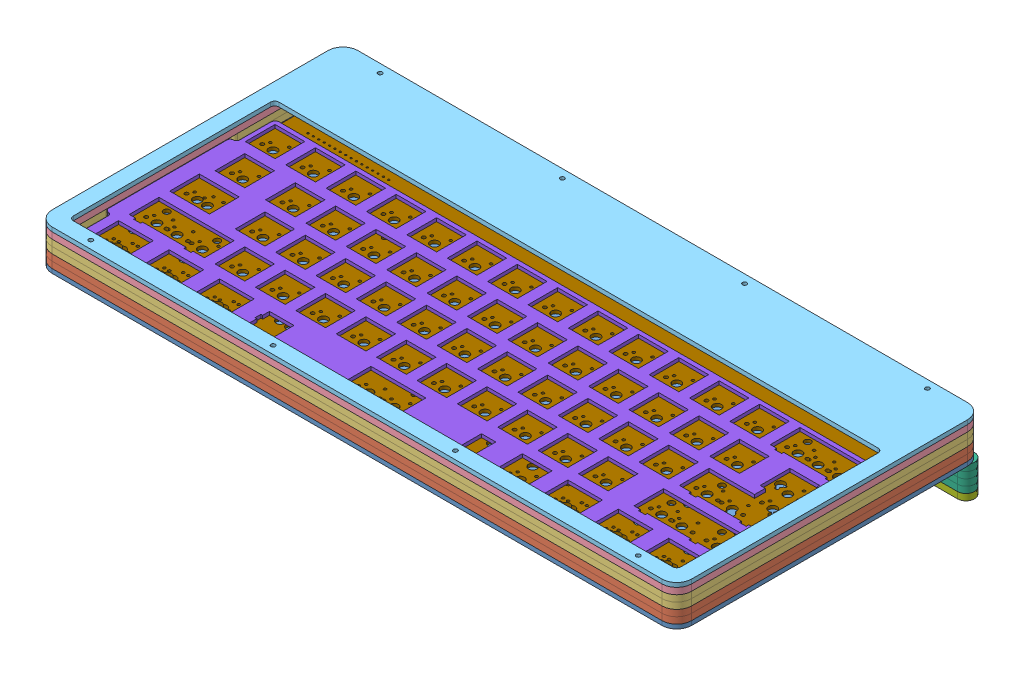
SolidWorks assembly case_stand, configuration Default. Lengths in mm.
Overall size (301.7 34 144.45).
14 component instances, 9 part files, 21 mates.
Components (placement in the parent):
- bottom_2mm-3: bottom_2mm [Default] at (-43.1764 265.3669 186.8003) size (301.7 2 144.2)
- usb_cutout_3mm-3: usb_cutout_3mm [Default] at (-56.4374 267.3669 142.5513) size (301.7 3 144.2)
- usb_cutout_3mm-4: usb_cutout_3mm [Default] at (-56.4374 270.3669 142.5513) size (301.7 3 144.2)
- gasket_layer_3mm-3: gasket_layer_3mm [Default] at (-28.4646 273.3669 125.7481) size (301.7 3 144.2)
- gasket_layer_3mm-4: gasket_layer_3mm [Default] at (-28.4646 276.3669 125.7481) size (301.7 3 144.2)
- middle_3mm-3: middle_3mm [Default] at (-40.4675 279.3669 150.7003) size (301.7 3 144.2)
- top_2mm-3: top_2mm [Default] at (-37.3053 282.3669 152.2912) size (301.7 2 144.2)
- stand_middle-2: stand_middle [Default] at (117.2615 262.3669 -16.2111) size (301.7 3 8)
- stand_middle-3: stand_middle [Default] at (117.2615 259.3669 -16.2111) size (301.7 3 8)
- stand_middle-4: stand_middle [Default] at (117.2615 256.3669 -16.2111) size (301.7 3 8)
- stand_middle-5: stand_middle [Default] at (117.2615 253.3669 -16.2111) size (301.7 3 8)
- stand_bottom-1: stand_bottom [Default] at (133.6627 250.3669 -23.7557) size (301.7 3 8)
- plate_1.6-1: plate_1.6 [Default] at (132.9907 275.5669 65.6331) size (290.7 1.6 99.17)
- pcb-1: pcb [Default] at (122.238 272.5669 51.8186) size (284.7 1.5 127.2)
Mates (geometry in assembly coordinates):
- Coincident6: coincident anti-aligned: plane of usb_cutout_3mm-3 through (-113.6191 394.2393 213.0391) normal (0 1 0); plane of usb_cutout_3mm-4 through (-113.6191 394.2393 213.0391) normal (0 -1 0)
- Coincident7: coincident aligned: circle of usb_cutout_3mm-3; cylinder of usb_cutout_3mm-4 through (205.6353 387.2393 186.5417) axis (0 1 0) radius 1.7
- Coincident8: coincident aligned: circle of usb_cutout_3mm-4; circle of gasket_layer_3mm-3
- Coincident9: coincident aligned: circle of gasket_layer_3mm-3; circle of gasket_layer_3mm-4
- Coincident11: coincident aligned: circle of stand_middle-2; circle of stand_middle-3
- Coincident12: coincident aligned: circle of stand_middle-3; circle of stand_middle-4
- Coincident13: coincident aligned: circle of stand_middle-4; circle of stand_middle-5
- Coincident14: coincident anti-aligned: plane of stand_middle-5 through (-12.6829 253.3669 -20.3956) normal (0 -1 0); plane of stand_bottom-1 through (-12.6829 253.3669 -20.3956) normal (0 1 0)
- Coincident15: coincident aligned: line of stand_middle-5 through (281.0164 253.3669 -24.3956) axis (-1 0 0); line of stand_bottom-1 through (281.0164 253.3669 -24.3956) axis (-1 0 0)
- Coincident16: coincident aligned: circle of stand_middle-5; circle of stand_bottom-1
- Coincident17: coincident aligned: circle of bottom_2mm-3; circle of stand_middle-2
- Distance5: distance = 1 mm anti-aligned: plane of plate_1.6-1 through (19.8171 277.1669 115.5539) normal (0 0 1); plane of gasket_layer_3mm-4 through (-28.4646 276.3669 116.5539) normal (0 0 -1)
- Distance6: distance = 1 mm anti-aligned: plane of plate_1.6-1 through (-11.1829 277.1669 92.0539) normal (-1 0 0); plane of gasket_layer_3mm-4 through (-12.1829 276.3669 125.7481) normal (1 0 0)
- Distance7: distance = 2.2 mm: line of plate_1.6-1 through (19.8171 275.5669 115.5539) axis (1 0 0); plane of usb_cutout_3mm-4 through (-56.4374 273.3669 142.5513) normal (0 1 0)
- Coincident25: coincident anti-aligned: circle of gasket_layer_3mm-4; circle of middle_3mm-3
- Concentric1: concentric anti-aligned: circle of middle_3mm-3; circle of top_2mm-3
- Coincident26: coincident anti-aligned: plane of middle_3mm-3 through (-97.6492 406.2393 221.1881) normal (0 1 0); plane of top_2mm-3 through (-94.4871 406.2393 222.779) normal (0 -1 0)
- Distance15: distance = 1.5 mm anti-aligned: plane of pcb-1 through (122.238 274.0669 51.8186) normal (0 1 0); plane of plate_1.6-1 through (15.8171 275.5669 113.5539) normal (0 -1 0)
- Distance16: distance = 1.5 mm: line of pcb-1 through (-8.1829 274.0669 109.5537) axis (0 0 -1); line of plate_1.6-1 through (-8.1829 275.5669 18.3843) axis (0 0 1)
- Distance17: distance = 1.5 mm: line of pcb-1 through (274.5162 274.0669 111.5539) axis (-1 0 0); line of plate_1.6-1 through (79.8171 275.5669 111.5539) axis (1 0 0)
- Coincident49: coincident anti-aligned: circle of bottom_2mm-3; circle of usb_cutout_3mm-3
